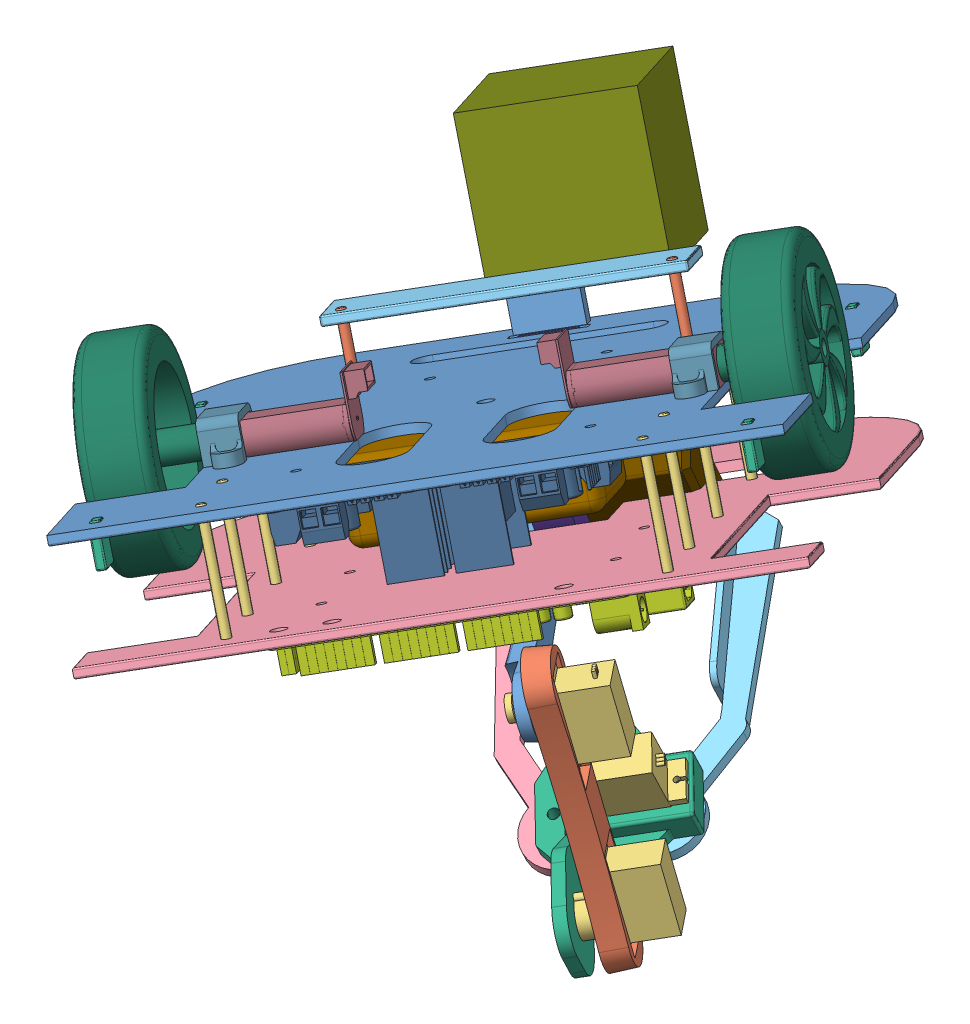
SolidWorks assembly Final, configuration Default. Lengths in mm.
Overall size (329.04 288.55 361.14).
63 component instances, 24 part files, 44 mates.
Components (placement in the parent):
- Bottom-1: Bottom [Default] at (240.0196 -450.3378 91.3935) x (-0.748912 -0.245301 0.615596) z (0.507001 0.38608 0.770644) size (200 13 200)
- IR spacer-1: IR spacer [Default] at (239.1963 -439.4844 21.6169) x (0.47109 0.063028 -0.87983) z (-0.772006 -0.453054 -0.445813) size (3 25 3)
- IR spacer-3: IR spacer [Default] at (171.7942 -461.5615 77.0205) x (-0.891758 -0.383365 0.240414) z (0.150621 0.249523 0.956583) size (3 25 3)
- spacer-1: spacer [Default] at (180.6754 -475.4215 106.6688) x (-0.764646 -0.452027 -0.459335) z (-0.482946 -0.07001 0.872847) size (3 40 3)
- spacer-2: spacer [Default] at (222.0799 -492.4598 150.2506) x (0.374411 0.339543 0.86286) z (-0.823247 -0.306498 0.477832) size (3 40 3)
- spacer-3: spacer [Default] at (257.57 -465.4342 204.1957) x (0.903913 0.413434 -0.109611) z (0.029349 0.195711 0.980222) size (3 40 3)
- spacer-4: spacer [Default] at (242.3599 -477.0166 181.0764) x (0.903814 0.412806 -0.112741) z (0.032236 0.19703 0.979867) size (3 40 3)
- spacer-5: spacer [Default] at (332.2294 -447.5805 107.2049) x (-0.365654 -0.003 0.930746) z (-0.827174 -0.457407 -0.326439) size (3 40 3)
- spacer-6: spacer [Default] at (311.9493 -463.0237 76.3791) x (0.625269 0.42171 0.656658) z (-0.65342 -0.177175 0.735969) size (3 40 3)
- spacer-7: spacer [Default] at (270.5449 -445.9854 32.7973) x (-0.164362 -0.255408 -0.95276) z (-0.889328 -0.379469 0.255144) size (3 40 3)
- spacer-8: spacer [Default] at (347.4394 -435.9981 130.3242) x (-0.36301 -0.001539 0.931784) z (-0.828337 -0.457414 -0.323464) size (3 40 3)
- top final-1: top final [Default] at (255.3811 -482.3509 97.3253) x (-0.748912 -0.245301 0.615596) z (0.507001 0.38608 0.770644) size (200 13 200)
- IR panel-1: IR panel [Default] at (204.4537 -455.5657 46.0422) x (0.748912 0.245301 -0.615596) z (0.507001 0.38608 0.770644) size (100 3 20)
- t sensor-1: t sensor [Default] at (148.2719 -499.2141 101.6269) x (-0.507001 -0.38608 -0.770644) z (-0.426709 0.889252 -0.164772) size (10 3 13)
- t sensor-2: t sensor [Default] at (220.5544 -443.1963 216.7584) x (0.507001 0.38608 0.770644) z (-0.426709 0.889252 -0.164772) size (10 3 13)
- t sensor-3: t sensor [Default] at (355.3585 -399.0421 105.9511) x (-0.507001 -0.38608 -0.770644) z (-0.426709 0.889252 -0.164772) size (10 3 13)
- t sensor-4: t sensor [Default] at (278.5826 -456.5317 -5.4867) x (0.507001 0.38608 0.770644) z (-0.426709 0.889252 -0.164772) size (10 3 13)
- ARDUINO MEGA-1: ARDUINO MEGA [Default] at (293.8708 -457.8048 148.3281) x (-0.748912 -0.245301 0.615596) z (0.507001 0.38608 0.770644) size (108 12.8 52)
- tcs34725-1: tcs34725 [Default] at (200.1491 -492.8286 26.0185) x (-0.748912 -0.245301 0.615596) z (0.426709 -0.889252 0.164772) size (20.3 2.67 20)
- batt-1: batt [Default] at (270.664 -428.9031 145.9212) x (0.507001 0.38608 0.770644) z (0.748912 0.245301 -0.615596) size (58.61 25 130.11)
- L298N Stepper Motor Driver Assembly-1: L298N Stepper Motor Driver Assembly [Default] at (255.5695 -426.9058 134.486) x (0.507001 0.38608 0.770644) z (0.748912 0.245301 -0.615596) size (43 28.01 43)
  - L298N Stepper Motor Driver (Red)-Part File-1: L298N Stepper Motor Driver (Red)-Part File [Default] at (16.8606 10.1012 32.1341) size (43 28.01 43)
  - pan head cross recess screw_iso_ISO 7045 - M1.6 x 4 - Z - 4N-1: pan head cross recess screw_iso_ISO 7045 - M1.6 x 4 - Z - 4N [Default] at (-1.3394 22.4012 35.9476) x (0 -1 0) z (-0.742963 0 0.669332) size (5.3 3.2 3.23)
  - pan head cross recess screw_iso_ISO 7045 - M1.6 x 4 - Z - 4N-2: pan head cross recess screw_iso_ISO 7045 - M1.6 x 4 - Z - 4N [Default] at (-1.3394 22.4012 41.5921) x (0 -1 0) z (-0.751552 0 0.659674) size (5.3 3.2 3.23)
  - pan head cross recess screw_iso_ISO 7045 - M1.6 x 4 - Z - 4N-3: pan head cross recess screw_iso_ISO 7045 - M1.6 x 4 - Z - 4N [Default] at (3.7852 22.4012 50.3107) x (0 -1 0) z (0.734198 0 -0.678936) size (5.3 3.2 3.23)
  - pan head cross recess screw_iso_ISO 7045 - M1.6 x 4 - Z - 4N-4: pan head cross recess screw_iso_ISO 7045 - M1.6 x 4 - Z - 4N [Default] at (14.2688 22.4012 50.3107) x (0 -1 0) z (0.720108 0 0.693862) size (5.3 3.2 3.23)
  - pan head cross recess screw_iso_ISO 7045 - M1.6 x 4 - Z - 4N-5: pan head cross recess screw_iso_ISO 7045 - M1.6 x 4 - Z - 4N [Default] at (9.027 22.4012 50.3107) x (0 -1 0) z (0.308372 0 0.951266) size (5.3 3.2 3.23)
  - pan head cross recess screw_iso_ISO 7045 - M1.6 x 4 - Z - 4N-6: pan head cross recess screw_iso_ISO 7045 - M1.6 x 4 - Z - 4N [Default] at (33.6606 22.4012 35.9476) x (0 -1 0) z (0 0 1) size (5.3 3.2 3.23)
  - pan head cross recess screw_iso_ISO 7045 - M1.6 x 4 - Z - 4N-7: pan head cross recess screw_iso_ISO 7045 - M1.6 x 4 - Z - 4N [Default] at (33.6606 22.4012 41.6421) x (0 -1 0) z (-0.222944 0 0.974831) size (5.3 3.2 3.23)
  - countersunk flat head cross recess screw_iso_ISO 7046-1 - M2.5 x 3 - Z - 3N-1: countersunk flat head cross recess screw_iso_ISO 7046-1 - M2.5 x 3 - Z - 3N [Default] at (16.3567 30.6012 21.6857) x (0 0 -1) z (1 0 0) size (3 4.7 4.7)
- L298N Stepper Motor Driver Assembly-2: L298N Stepper Motor Driver Assembly [Default] at (286.3475 -409.4056 149.2271) x (-0.507001 -0.38608 -0.770644) z (-0.748912 -0.245301 0.615596) size (43 28.01 43)
  - L298N Stepper Motor Driver (Red)-Part File-1: L298N Stepper Motor Driver (Red)-Part File [Default] at (16.8606 10.1012 32.1341) size (43 28.01 43)
  - pan head cross recess screw_iso_ISO 7045 - M1.6 x 4 - Z - 4N-1: pan head cross recess screw_iso_ISO 7045 - M1.6 x 4 - Z - 4N [Default] at (-1.3394 22.4012 35.9476) x (0 -1 0) z (-0.742963 0 0.669332) size (5.3 3.2 3.23)
  - pan head cross recess screw_iso_ISO 7045 - M1.6 x 4 - Z - 4N-2: pan head cross recess screw_iso_ISO 7045 - M1.6 x 4 - Z - 4N [Default] at (-1.3394 22.4012 41.5921) x (0 -1 0) z (-0.751552 0 0.659674) size (5.3 3.2 3.23)
  - pan head cross recess screw_iso_ISO 7045 - M1.6 x 4 - Z - 4N-3: pan head cross recess screw_iso_ISO 7045 - M1.6 x 4 - Z - 4N [Default] at (3.7852 22.4012 50.3107) x (0 -1 0) z (0.734198 0 -0.678936) size (5.3 3.2 3.23)
  - pan head cross recess screw_iso_ISO 7045 - M1.6 x 4 - Z - 4N-4: pan head cross recess screw_iso_ISO 7045 - M1.6 x 4 - Z - 4N [Default] at (14.2688 22.4012 50.3107) x (0 -1 0) z (0.720108 0 0.693862) size (5.3 3.2 3.23)
  - pan head cross recess screw_iso_ISO 7045 - M1.6 x 4 - Z - 4N-5: pan head cross recess screw_iso_ISO 7045 - M1.6 x 4 - Z - 4N [Default] at (9.027 22.4012 50.3107) x (0 -1 0) z (0.308372 0 0.951266) size (5.3 3.2 3.23)
  - pan head cross recess screw_iso_ISO 7045 - M1.6 x 4 - Z - 4N-6: pan head cross recess screw_iso_ISO 7045 - M1.6 x 4 - Z - 4N [Default] at (33.6606 22.4012 35.9476) x (0 -1 0) z (0 0 1) size (5.3 3.2 3.23)
  - pan head cross recess screw_iso_ISO 7045 - M1.6 x 4 - Z - 4N-7: pan head cross recess screw_iso_ISO 7045 - M1.6 x 4 - Z - 4N [Default] at (33.6606 22.4012 41.6421) x (0 -1 0) z (-0.222944 0 0.974831) size (5.3 3.2 3.23)
  - countersunk flat head cross recess screw_iso_ISO 7046-1 - M2.5 x 3 - Z - 3N-1: countersunk flat head cross recess screw_iso_ISO 7046-1 - M2.5 x 3 - Z - 3N [Default] at (16.3567 30.6012 21.6857) x (0 0 -1) z (1 0 0) size (3 4.7 4.7)
- wheel motor assembly-6: wheel motor assembly [Default] at (269.8565 -435.1542 185.6104) x (-0.128378 -0.239904 -0.962271) z (-0.426709 0.889252 -0.164772) size (71.05 85.11 65)
  - micro motor assembly-1: micro motor assembly [Default] at (54.6346 42.2185 20.0539) x (0 -1 0) z (-1 0 0) size (57.18 19.3 37.83)
    - Part1-1: Part1 [Default] x (0.437378 0 0.899278) z (-0.899278 0 0.437378) size (14.6 19.3 56.48)
  - Part2_1-1: Part2_1 [Default] at (46.6525 58.6304 14.7539) x (-0.899278 -0.437378 0) z (-0.437378 0.899278 0) size (29.6 12.6 11.51)
  - wheel1-1: wheel1 [Default] at (31.891 88.981 20.0539) x (-0.899278 -0.437378 0) z (0 0 1) size (65 28.8 65)
- wheel motor assembly-8: wheel motor assembly [Default] at (249.1379 -471.6852 42.1121) x (0.128378 0.239904 0.962271) z (-0.426709 0.889252 -0.164772) size (71.05 85.11 65)
  - micro motor assembly-1: micro motor assembly [Default] at (54.6346 42.2185 20.0539) x (0 -1 0) z (-1 0 0) size (57.18 19.3 37.83)
    - Part1-1: Part1 [Default] x (0.437378 0 0.899278) z (-0.899278 0 0.437378) size (14.6 19.3 56.48)
  - Part2_1-1: Part2_1 [Default] at (46.6525 58.6304 14.7539) x (-0.899278 -0.437378 0) z (-0.437378 0.899278 0) size (29.6 12.6 11.51)
  - wheel1-1: wheel1 [Default] at (31.891 88.981 20.0539) x (-0.899278 -0.437378 0) z (0 0 1) size (65 28.8 65)
- box-1: box [Default] at (118.2663 -528.6604 -99.663) x (0.507001 0.38608 0.770644) z (-0.748912 -0.245301 0.615596) size (50 50 50)
- 3D_model assem_2-1: 3D_model assem_2 [Default] at (183.8602 -480.6338 -9.7655) x (-0.748912 -0.245301 0.615596) z (0.507001 0.38608 0.770644) size (136.22 165.98 149.6) (flexible)
  - Waist_r1-2: Waist_r1 [Default] at (12.283 16.6911 88.1271) size (60 61.78 65.42)
  - Servo Motor MG996R_r1-1: Servo Motor MG996R_r1 [Default] at (-33.917 49.7197 81.4564) x (0 -0.707107 0.707107) z (0 0.707107 0.707107) size (55.8 47.4 20.5)
  - sub_Arm 1-1: sub_Arm 1 [Default] at (8.283 73.667 110.5559) x (0 0.417487 0.908683) z (0 0.908683 -0.417487) size (105 8.09 20)
  - sub_Arm 2-1: sub_Arm 2 [Default] at (8.283 121.7663 134.3933) x (0 0.929532 -0.368741) z (0 0.368741 0.929532) size (100 8 20)
  - Servo Motor Micro  9g-1: Servo Motor Micro  9g [Default] at (-14.017 95.1071 145.0226) x (0 0.929532 -0.368741) z (0 -0.368741 -0.929532) size (32.6 29.9 12.4)
  - Servo Motor Micro  9g-2: Servo Motor Micro  9g [Default] at (-13.517 147.9791 123.9948) x (0 -0.929532 0.368741) z (0 0.368741 0.929532) size (32.6 29.9 12.4)
  - Gripper Assembly-1: Gripper Assembly [Default] at (5.056 168.7939 129.6486) x (-1 0 0) z (0 -0.753254 -0.65773) size (136.22 44.05 146.84)
    - gear1-1: gear1 [Default] at (-21.7851 12.6028 63.9798) x (-0.470802 0 0.882239) z (-0.882239 0 -0.470802) size (100.29 20 52.85)
    - gear2-1: gear2 [Default] at (4.4928 12.6028 46.5084) x (-0.53236 0 -0.846518) z (0.846518 0 -0.53236) size (104.78 20 41.35)
    - Gripper base-1: Gripper base [Default] at (-22.027 4.1028 80.0636) size (44.4 28 77)
    - Servo Motor Micro  9g-1: Servo Motor Micro  9g [Default] at (4.773 -19.4472 55.0636) x (-1 0 0) z (0 0 -1) size (32.6 29.9 12.4)
Mates (geometry in assembly coordinates):
- Coincident28: coincident anti-aligned: circle of Bottom-1; circle of IR spacer-1
- Concentric13: concentric aligned: cylinder of Bottom-1 through (180.8888 -475.8661 106.7512) axis (0.426709 -0.889252 0.164772) radius 1.5; circle of spacer-1
- Coincident71: coincident anti-aligned: plane of Bottom-1 through (240.0196 -450.3378 91.3935) normal (-0.426709 0.889252 -0.164772); circle of spacer-1
- Concentric14: concentric anti-aligned: cylinder of Bottom-1 through (205.2249 -457.3343 143.7421) axis (0.426709 -0.889252 0.164772) radius 1.5; circle of spacer-2
- Coincident73: coincident anti-aligned: plane of Bottom-1 through (240.0196 -450.3378 91.3935) normal (-0.426709 0.889252 -0.164772); circle of spacer-2
- Concentric15: concentric aligned: cylinder of Bottom-1 through (240.715 -430.3088 197.6872) axis (0.426709 -0.889252 0.164772) radius 1.5; cylinder of spacer-3 through (240.5016 -429.8641 197.6048) axis (0.426709 -0.889252 0.164772) radius 1.5
- Coincident74: coincident anti-aligned: plane of Bottom-1 through (240.0196 -450.3378 91.3935) normal (-0.426709 0.889252 -0.164772); circle of spacer-3
- Coincident75: coincident aligned: cylinder of Bottom-1 through (225.5049 -441.8911 174.5679) axis (0.426709 -0.889252 0.164772) radius 1.5; circle of spacer-4
- Coincident76: coincident anti-aligned: plane of Bottom-1 through (240.0196 -450.3378 91.3935) normal (-0.426709 0.889252 -0.164772); circle of spacer-4
- Coincident85: coincident anti-aligned: circle of IR spacer-3; plane of IR panel-1 through (203.1736 -452.8979 45.5479) normal (-0.426709 0.889252 -0.164772)
- Concentric18: concentric anti-aligned: circle of IR spacer-1; circle of IR panel-1
- Concentric19: concentric anti-aligned: circle of spacer-3; cylinder of top final-1 through (256.0765 -462.3218 203.619) axis (0.426709 -0.889252 0.164772) radius 1.5
- Coincident87: coincident anti-aligned: circle of spacer-1; cylinder of top final-1 through (196.2503 -507.8792 112.683) axis (0.426709 -0.889252 0.164772) radius 1.5
- Coincident88: coincident anti-aligned: circle of spacer-3; plane of top final-1 through (256.6612 -485.0187 97.8196) normal (0.426709 -0.889252 0.164772)
- Parallel18: parallel aligned: plane of Bottom-1 through (217.1086 -438.9278 230.5118) normal (-0.748912 -0.245301 0.615596); plane of t sensor-1 through (146.0252 -499.95 103.4737) normal (-0.748912 -0.245301 0.615596)
- Coincident104: coincident anti-aligned: plane of Bottom-1 through (219.2616 -436.8956 217.6964) normal (0.748912 0.245301 -0.615596); plane of t sensor-2 through (220.5544 -443.1963 216.7584) normal (-0.748912 -0.245301 0.615596)
- Coincident105: coincident anti-aligned: plane of Bottom-1 through (218.9734 -438.0901 211.9964) normal (0.507001 0.38608 0.770644); plane of t sensor-2 through (216.5133 -438.3814 213.7608) normal (-0.507001 -0.38608 -0.770644)
- Coincident106: coincident: plane of Bottom-1 through (240.0196 -450.3378 91.3935) normal (-0.426709 0.889252 -0.164772); line of t sensor-2 through (219.0081 -437.0887 217.311) axis (-0.507001 -0.38608 -0.770644)
- Coincident113: coincident anti-aligned: plane of Bottom-1 through (144.7324 -493.6493 104.4117) normal (-0.507001 -0.38608 -0.770644); plane of t sensor-1 through (146.7658 -492.4688 102.4825) normal (0.507001 0.38608 0.770644)
- Coincident114: coincident anti-aligned: line of Bottom-1 through (142.1974 -495.5797 100.5585) axis (0.507001 0.38608 0.770644); line of t sensor-1 through (144.4789 -493.8424 104.0264) axis (-0.507001 -0.38608 -0.770644)
- Concentric26: concentric anti-aligned: cylinder of IR spacer-3 through (182.4619 -483.7928 81.1398) axis (-0.426709 0.889252 -0.164772) radius 1.5; cylinder of IR panel-1 through (172.0076 -462.0061 77.1029) axis (0.426709 -0.889252 0.164772) radius 1.5
- Coincident127: coincident anti-aligned: plane of top final-1 through (256.6612 -485.0187 97.8196) normal (0.426709 -0.889252 0.164772); plane of ARDUINO MEGA-1 through (313.01 -457.8714 98.4036) normal (-0.426709 0.889252 -0.164772)
- Concentric27: concentric anti-aligned: cylinder of top final-1 through (321.108 -434.0381 145.3679) axis (0.426709 -0.889252 0.164772) radius 2.5; axis of ARDUINO MEGA-1 through (326.1431 -444.5313 147.3122) axis (-0.426709 0.889252 -0.164772)
- Parallel29: parallel aligned: plane of top final-1 through (208.5045 -511.0823 142.559) normal (-0.748912 -0.245301 0.615596); plane of ARDUINO MEGA-1 through (245.8596 -476.5069 171.7293) normal (-0.748912 -0.245301 0.615596)
- Coincident139: coincident anti-aligned: plane of Bottom-1 through (187.6724 -486.6251 31.119) normal (-0.507001 -0.38608 -0.770644); plane of tcs34725-1 through (191.2667 -488.0615 29.474) normal (0.507001 0.38608 0.770644)
- Coincident141: coincident aligned: plane of Bottom-1 through (240.0196 -450.3378 91.3935) normal (-0.426709 0.889252 -0.164772); plane of tcs34725-1 through (200.7442 -482.7068 18.4138) normal (-0.426709 0.889252 -0.164772)
- Distance7: distance = 1 mm: line of Bottom-1 through (203.9076 -485.0545 15.7583) axis (0.507001 0.38608 0.770644); line of tcs34725-1 through (203.7303 -484.3424 17.2687) axis (0.507001 0.38608 0.770644)
- Coincident144: coincident anti-aligned: plane of Bottom-1 through (241.2997 -453.0056 91.8878) normal (0.426709 -0.889252 0.164772); plane of batt-1 through (270.664 -428.9031 145.9212) normal (-0.426709 0.889252 -0.164772)
- Parallel34: parallel aligned: plane of Bottom-1 through (115.7083 -516.1437 76.383) normal (-0.507001 -0.38608 -0.770644); plane of batt-1 through (225.7498 -483.5957 118.7916) normal (-0.507001 -0.38608 -0.770644)
- Distance10: distance = 34 mm: line of Bottom-1 through (219.9239 -446.6962 181.2957) axis (-0.507001 -0.38608 -0.770644); cylinder of batt-1 through (219.7846 -463.9402 112.869) axis (-0.507001 -0.38608 -0.770644) radius 4
- Coincident146: coincident anti-aligned: plane of Bottom-1 through (241.2997 -453.0056 91.8878) normal (0.426709 -0.889252 0.164772); plane of L298N Stepper Motor Driver Assembly-1/L298N Stepper Motor Driver (Red)-Part File-1 through (292.4938 -421.4963 129.3622) normal (-0.426709 0.889252 -0.164772)
- Distance11: distance = 55 mm: line of L298N Stepper Motor Driver Assembly-1/L298N Stepper Motor Driver (Red)-Part File-1 through (297.6948 -424.5231 99.5581) axis (0.507001 0.38608 0.770644); line of Bottom-1 through (346.49 -405.2403 77.26) axis (0.507001 0.38608 0.770644)
- Distance12: distance = 11 mm: line of L298N Stepper Motor Driver Assembly-1/L298N Stepper Motor Driver (Red)-Part File-1 through (319.4959 -407.9217 132.6958) axis (-0.748912 -0.245301 0.615596); line of Bottom-1 through (366.2631 -390.1832 107.3151) axis (-0.748912 -0.245301 0.615596)
- Coincident150: coincident anti-aligned: plane of wheel motor assembly-6/Part2_1-1 through (196.2148 -460.9456 147.5862) normal (0.426709 -0.889252 0.164772); plane of Bottom-1 through (240.0196 -450.3378 91.3935) normal (-0.426709 0.889252 -0.164772)
- Coincident151: coincident aligned: plane of Bottom-1 through (188.0729 -482.93 128.9208) normal (-0.748912 -0.245301 0.615596); plane of wheel motor assembly-6/micro motor assembly-1/Part1-1 through (199.8755 -446.5017 157.7952) normal (-0.748912 -0.245301 0.615596)
- Distance13: distance = 65 mm: line of wheel motor assembly-6/Part2_1-1 through (205.3408 -453.9961 161.4577) axis (0.748912 0.245301 -0.615596); line of Bottom-1 through (365.6109 -387.1998 106.8983) axis (-0.748912 -0.245301 0.615596)
- Coincident152: coincident anti-aligned: plane of Bottom-1 through (240.0196 -450.3378 91.3935) normal (-0.426709 0.889252 -0.164772); plane of wheel motor assembly-8/Part2_1-1 through (301.9243 -425.9471 62.7128) normal (0.426709 -0.889252 0.164772)
- Coincident153: coincident aligned: plane of Bottom-1 through (292.9206 -448.5878 42.7374) normal (0.748912 0.245301 -0.615596); plane of wheel motor assembly-8/micro motor assembly-1/Part1-1 through (298.3349 -417.0242 61.9017) normal (0.748912 0.245301 -0.615596)
- Distance14: distance = 65 mm: line of Bottom-1 through (365.6109 -387.1998 106.8983) axis (-0.748912 -0.245301 0.615596); line of wheel motor assembly-8/Part2_1-1 through (310.1884 -419.654 75.2743) axis (-0.748912 -0.245301 0.615596)
- Parallel36: parallel aligned: plane of Bottom-1 through (366.891 -389.8675 107.3926) normal (0.748912 0.245301 -0.615596); plane of box-1 through (118.2663 -528.6604 -99.663) normal (0.748912 0.245301 -0.615596)
- Coincident154: coincident anti-aligned: plane of Bottom-1 through (241.2997 -453.0056 91.8878) normal (0.426709 -0.889252 0.164772); plane of 3D_model assem_2-1/Waist_r1-2 through (226.4641 -464.4653 68.4607) normal (-0.426709 0.889252 -0.164772)
- Parallel37: parallel aligned: plane of Bottom-1 through (217.1086 -438.9278 230.5118) normal (-0.748912 -0.245301 0.615596); plane of 3D_model assem_2-1/Waist_r1-2 through (229.4597 -463.4841 65.9983) normal (-0.748912 -0.245301 0.615596)
- Distance15: distance = 100 mm: line of 3D_model assem_2-1/Waist_r1-2 through (227.7442 -467.1331 68.955) axis (-0.426709 0.889252 -0.164772); line of Bottom-1 through (161.4594 -481.4669 145.0478) axis (-0.507001 -0.38608 -0.770644)
- Distance16: distance = 40 mm: line of 3D_model assem_2-1/Waist_r1-2 through (227.7442 -467.1331 68.955) axis (-0.426709 0.889252 -0.164772); line of Bottom-1 through (228.2769 -472.6721 19.4749) axis (-0.748912 -0.245301 0.615596)
